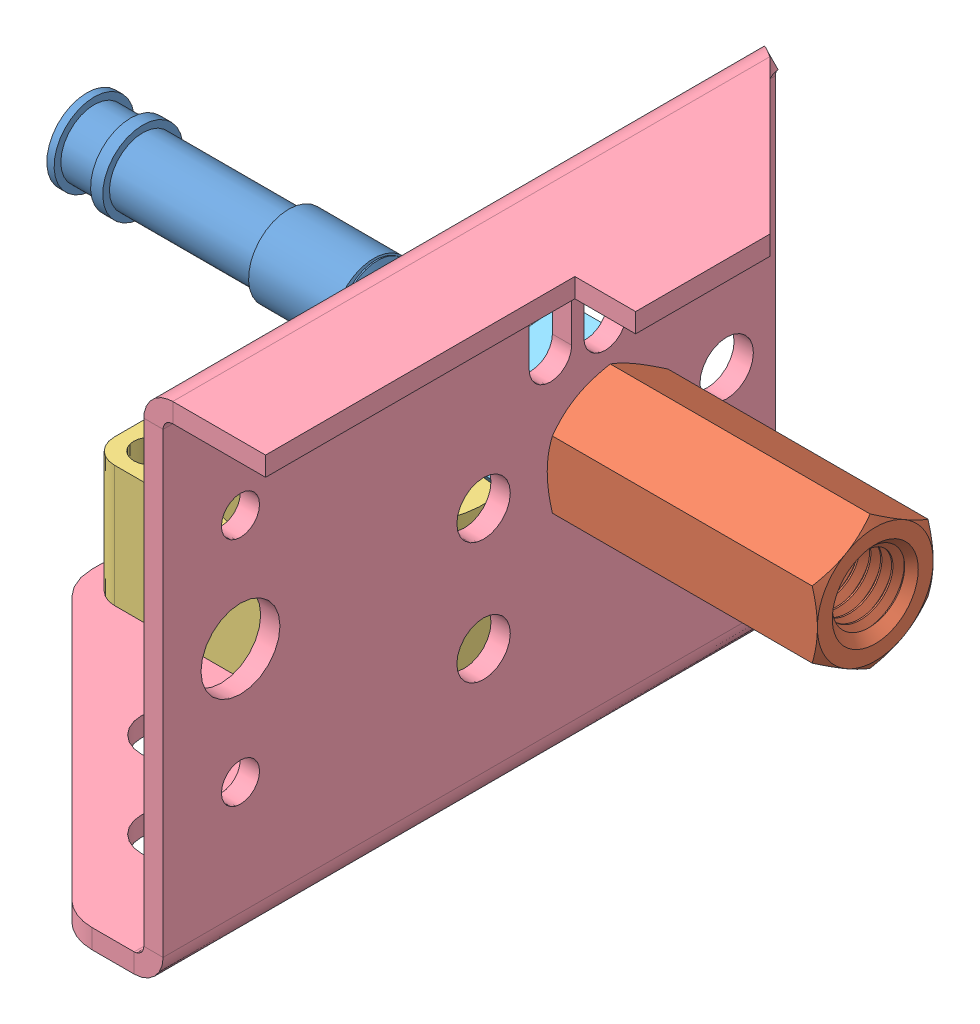
SolidWorks assembly Nozzle_02, configuration Default. Lengths in mm.
Overall size (106.61 63.53 61.4).
6 component instances, 6 part files, 17 mates.
Components (placement in the parent):
- D0001-1: D0001 [Default] at (23.77 0 0) (suppressed, hidden)
- Nozzle_02-2: Nozzle_02 [92196A333] at (6.5217 0 -30) x (0 -0.248007 -0.968758) z (1 0 0) size (7.33 6.63 50.7)
- Coupling-1-4x28_90268A325-1: Coupling-1-4x28_90268A325 [No machining] at (22.225 0 -30) x (0 0 -1) z (1 0 0) size (9.53 11 22.44)
- Fan_25x25x10-1: Fan_25x25x10 [Default] at (-17.3813 -14.6069 -30) x (1 0 0) z (0 1 0) size (25 25 10)
- E_MountPlate^Nozzle_02-1: E_MountPlate^Nozzle_02 [Default] x (0 0 -1) z (1 0 0) size (50.37 42.39 44.81) (virtual)
- Thin_1-4x28_92101A320-1: Thin_1-4x28_92101A320 [92101A320] at (-5.5563 0 -30) x (0 -0.669166 0.743113) z (-1 0 0) size (11.11 12.83 4.59)
Mates (geometry in assembly coordinates):
- Coincident1: coincident aligned: plane of D0001-1 through (23.77 0 0) normal (0 0 1); plane of assembly through (0 0 0) normal (0 0 1)
- Coincident2: coincident aligned: plane of D0001-1 through (23.77 0 0) normal (0 1 0); plane of assembly through (0 0 0) normal (0 1 0)
- Concentric1: concentric: cylinder of ? through (10.5217 0 -30) axis (1 0 0) radius 2.75
- Concentric4: concentric anti-aligned: circle of Coupling-1-4x28_90268A325-1; circle of assembly
- Coincident4: coincident anti-aligned: plane of D0001-1 through (0 19.06 -6.365) normal (-1 0 0); plane of assembly through (0 0 0) normal (1 0 0)
- Parallel1: parallel anti-aligned: plane of Coupling-1-4x28_90268A325-1 through (22.225 0 -30) normal (0 0 -1); plane of assembly through (0 0 0) normal (0 0 1)
- InPlace1: in place: plane of E_MountPlate^Nozzle_02-1 through (0 0 0) normal (1 0 0); moOrthogonalPlaneRef_w of E_MountPlate^Nozzle_02-1 through (-55 0 0) axis (0 0 1); plane of E_MountPlate^Nozzle_02-1 through (0 0 0) normal (0 0 -1); unknown of E_MountPlate^Nozzle_02-1
- Coincident9: coincident aligned: plane of E_MountPlate^Nozzle_02-1; plane of assembly
- Coincident10: coincident aligned: plane of E_MountPlate^Nozzle_02-1; moOrthogonalPlaneRef_w of assembly
- Coincident11: coincident anti-aligned: plane of E_MountPlate^Nozzle_02-1 through (0 0 0) normal (0 0 -1); moOrthogonalPlaneRef_w of assembly
- Concentric8: concentric anti-aligned: circle of Coupling-1-4x28_90268A325-1; circle of Thin_1-4x28_92101A320-1
- Coincident14: coincident anti-aligned: plane of Coupling-1-4x28_90268A325-1 through (0 5.4993 -30) normal (-1 0 0); plane of E_MountPlate^Nozzle_02-1 through (0 23.06 6.365) normal (1 0 0)
- Coincident15: coincident anti-aligned: plane of E_MountPlate^Nozzle_02-1 through (-1.5875 23.06 6.365) normal (-1 0 0); plane of Thin_1-4x28_92101A320-1 through (-1.5875 4.7677 -25.7068) normal (1 0 0)
- Distance1: distance = 44 mm aligned: plane of assembly through (0 0 0) normal (1 0 0); plane of Nozzle_02-2 through (-44 0 -30) normal (1 0 0)
- Tangent1: tangent aligned: cylinder of Fan_25x25x10-1 through (-7.3812 -19.6069 -20) axis (0 1 0) radius 1.4; cylinder of E_MountPlate^Nozzle_02-1 through (-7.3812 -21.1944 -20) axis (0 1 0) radius 1.4
- Concentric9: concentric aligned: cylinder of Fan_25x25x10-1 through (-7.3812 -19.6069 -40) axis (0 1 0) radius 1.4; cylinder of E_MountPlate^Nozzle_02-1 through (-7.3812 -21.1944 -40) axis (0 1 0) radius 1.4
- Coincident17: coincident anti-aligned: plane of Fan_25x25x10-1 through (-29.8813 -19.6069 -17.5) normal (0 -1 0); plane of E_MountPlate^Nozzle_02-1 through (41.9856 -19.6069 6.365) normal (0 1 0); axis of D0001-1
